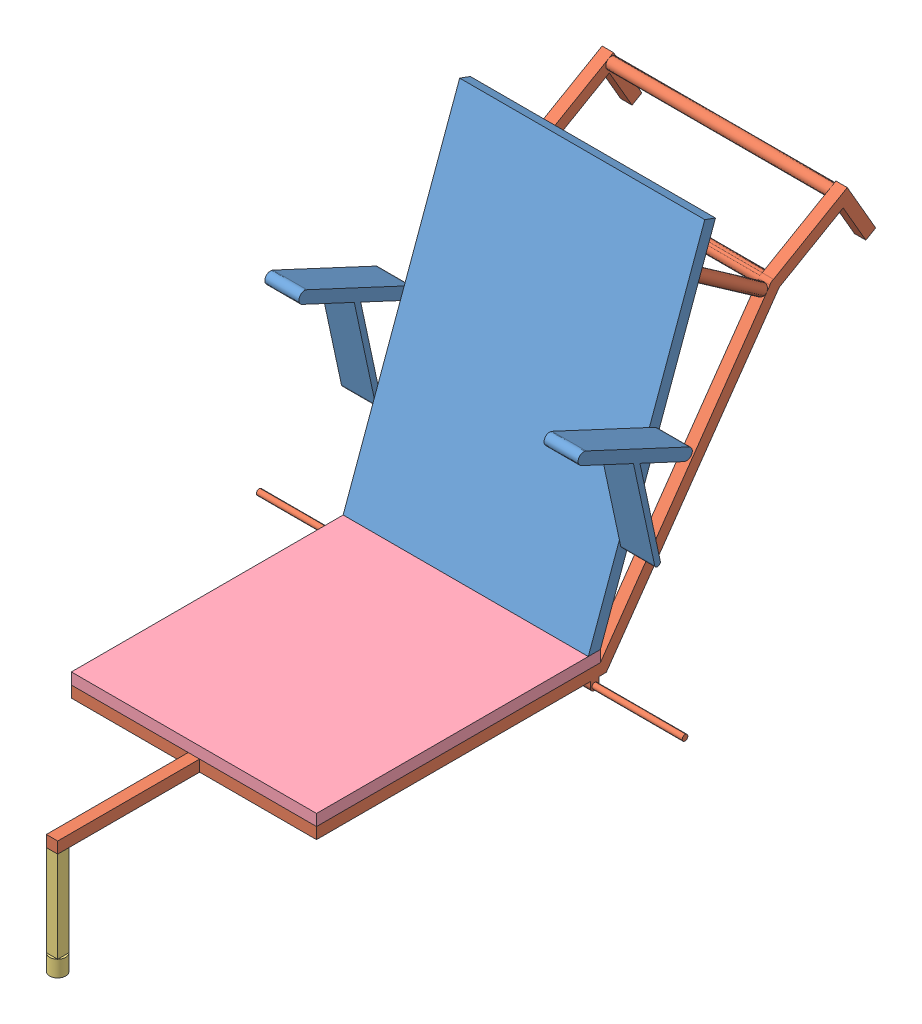
SolidWorks assembly Frame Assembly, configuration Default. Lengths in mm.
Overall size (750 792.79 1239.05).
4 component instances, 4 part files, 6 mates.
Components (placement in the parent):
- BackAndArmRest-1: BackAndArmRest [Default] at origin size (551.8 563.82 302.02)
- Frame-1: Frame [Default] at (0 -20 0) x (0 0 -1) z (1 0 0) size (1234.91 555.15 750)
- CasterWheelMount-1: CasterWheelMount [Default] at (0 -200.4 740) size (28.28 188.97 28.28)
- Seat-1: Seat [Default] at origin size (431.8 20 500)
Mates (geometry in assembly coordinates):
- Coincident1: coincident: plane of Seat-1 through (215.9 0 0) normal (0 1 0); plane of BackAndArmRest-1 through (215.9 0 0) normal (0 -1 0)
- Coincident2: coincident: line of Seat-1 through (431.8 215.9 0) axis (0 -1 0); line of BackAndArmRest-1 through (431.8 215.9 0) axis (0 -1 0)
- Coincident3: coordinate: point of Seat-1; point of BackAndArmRest-1
- Coincident11: coincident: plane of Seat-1 through (215.9 -20 0) normal (0 -1 0); plane of Frame-1 through (0 -20 0) normal (0 1 0)
- Coincident22: coincident: plane of Frame-1 through (0 -40 750) normal (0 0 1); plane of CasterWheelMount-1 through (0 -40 750) normal (0 0 1)
- Coincident23: coincident: plane of Frame-1 through (0 -40 0) normal (0 -1 0); plane of CasterWheelMount-1 through (0 -40 740) normal (0 1 0)
